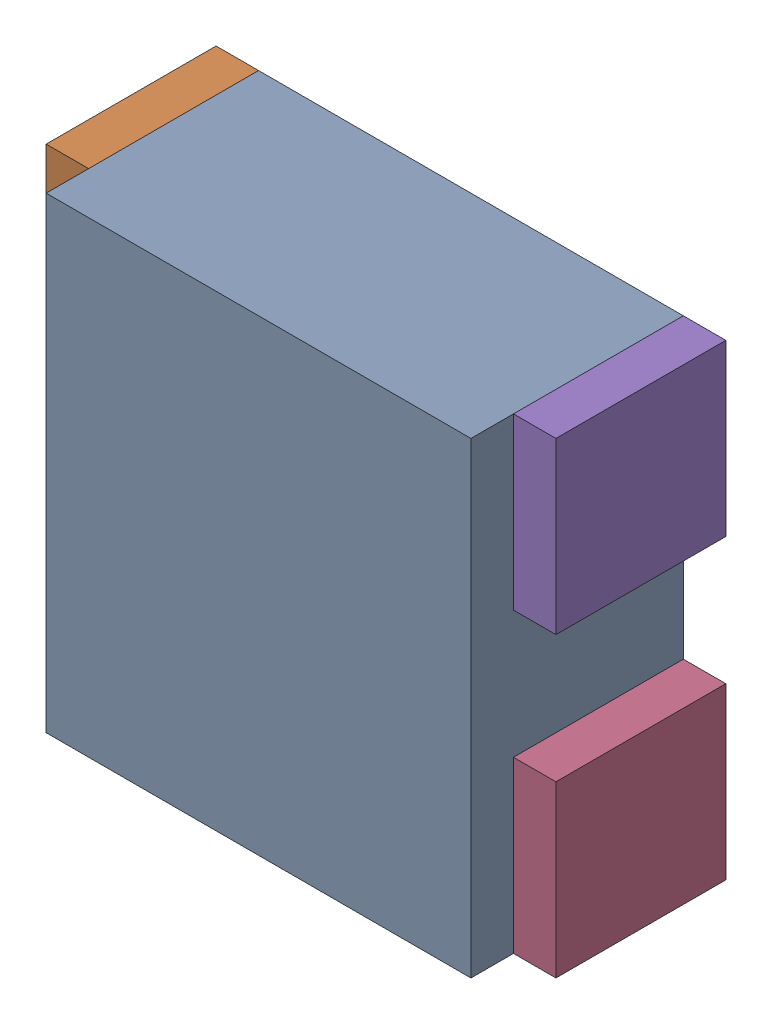
SolidWorks assembly RN16, configuration Default. Lengths in mm.
Overall size (1.2 1.1 0.5).
10 component instances, 2 part files, 0 mates.
Components (placement in the parent):
- 836749552-1: 836749552 [Default] at (116.65 63.1 0) size (1 1.1 0.5)
  - Extruded_11-1: Extruded_11 [Default] at origin size (1 1.1 0.5)
- 791587232-1: 791587232 [Default] at (116.1 63.45 0) size (0.1 0.4 0.4)
  - Extruded_10-1: Extruded_10 [Default] at origin size (0.1 0.4 0.4)
- 791587232-2: 791587232 [Default] at (116.1 62.75 0) size (0.1 0.4 0.4)
  - Extruded_10-1: Extruded_10 [Default] at origin size (0.1 0.4 0.4)
- 791587232-3: 791587232 [Default] at (117.2 62.75 0) size (0.1 0.4 0.4)
  - Extruded_10-1: Extruded_10 [Default] at origin size (0.1 0.4 0.4)
- 791587232-4: 791587232 [Default] at (117.2 63.45 0) size (0.1 0.4 0.4)
  - Extruded_10-1: Extruded_10 [Default] at origin size (0.1 0.4 0.4)
